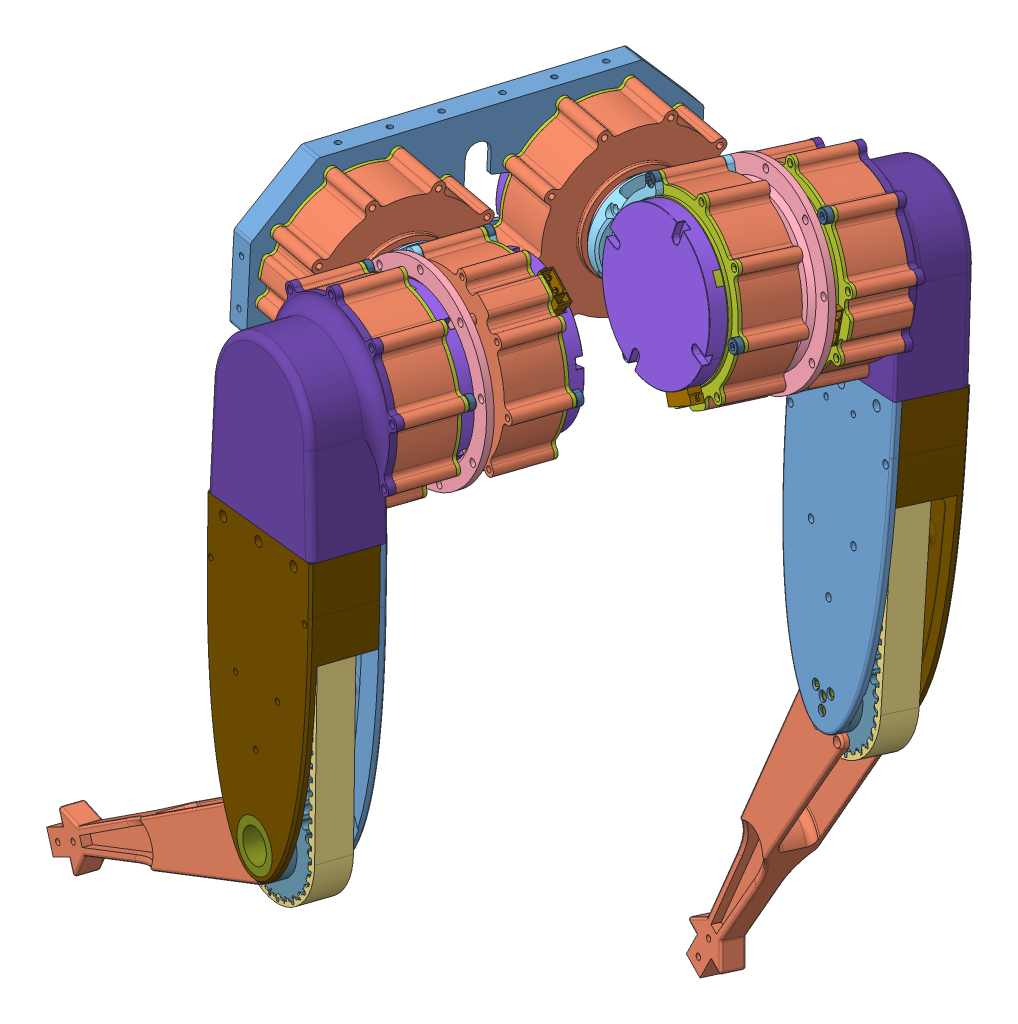
SolidWorks assembly 机器狗-后腿, configuration 默认. Lengths in mm.
Overall size (324.11 409.94 394.79).
151 component instances, 23 part files, 5 mates.
Components (placement in the parent):
- 肩膀-1: 肩膀 [默认] at (23.8945 164.324 448.6383) x (-0.213046 0.068534 0.974636) z (0.017935 -0.997094 0.074033) size (175 10 85)
- 右后机械腿装配体-1: 右后机械腿装配体 [默认] at (42.485 112.8434 831.0435) x (-0.961203 -0.272852 -0.040505) z (0.193141 -0.560888 -0.805047) size (251.73 287.49 164.5)
  - CyberGearmotor.stp-1: CyberGearmotor.stp [默认] at (-142.9395 145.7297 202.822) x (0.962425 -0.140801 0.232192) z (-0.142242 0.466971 0.872757) size (96.28 96.17 36.5)
    - ASM0002_ASM_1_ASM.stp-1: ASM0002_ASM_1_ASM.stp [默认] at origin size (96.28 96.17 36.5)
      - ASM0002_ASM_1_ASM_1_ASM.stp-1: ASM0002_ASM_1_ASM_1_ASM.stp [默认] at origin size (96.28 96.17 36.5)
        - 0714_ASM_1_ASM_1_ASM_1_ASM.stp-1: 0714_ASM_1_ASM_1_ASM_1_ASM.stp [默认] at origin size (96.28 96.17 36.5)
          - 3_1_02_067_0003_ASM_ASM_1_ASM_1_ASM.stp-1: 3_1_02_067_0003_ASM_ASM_1_ASM_1_ASM.stp [默认] at origin size (96.28 96.17 36.5)
            - 3_1_02_067_0003_ASM_1_ASM_1_ASM_ASM.stp-1: 3_1_02_067_0003_ASM_1_ASM_1_ASM_ASM.stp [默认] at origin size (96.28 96.17 36.5)
              - 1_1_06_EB673-504_1_1_1_1_1.stp-1: 1_1_06_EB673-504_1_1_1_1_1.stp [默认] at (39.8324 39.833 -22) size (79.19 78.95 25.5)
              - 1_2_04_670601_1_1_1_1_1.stp-1: 1_2_04_670601_1_1_1_1_1.stp [默认] at (93.9161 79.9966 -44) size (37 37 4)
              - 1_1_02_EB671-500_1_1_1_1_1.stp-1: 1_1_02_EB671-500_1_1_1_1_1.stp [默认] at (93.9161 79.9966 -44.4) x (-0.960973 0.276644 0) z (0 0 1) size (33 33 8.5)
              - 1_2_04_694000_1_1_1_1_1.stp-1: 1_2_04_694000_1_1_1_1_1.stp [默认] at (93.9161 79.9966 -44.5) size (11 11 4)
              - 1_2_06_000213_1_1_1_1_1.stp-1: 1_2_06_000213_1_1_1_1_1.stp [默认] at (93.9161 79.9966 -45.5) size (38.8 36.2 1.5)
              - 1_1_31_QT-642_1_1_1_1_1.stp-1: 1_1_31_QT-642_1_1_1_1_1.stp [默认] at (93.9161 79.9966 -22) x (-0.970555 -0.24088 0) z (0 0 -1) size (79.5 79.36 6)
              - 1_1_06_EB673-502_1_1_1_1_1.stp-1: 1_1_06_EB673-502_1_1_1_1_1.stp [默认] at (93.9161 79.9966 -13) x (-0.515958 -0.856614 0) z (0 0 -1) size (63 63 8)
            - 0518_ASM_2_ASM_1_ASM_1_ASM_1_AS_ASM.stp-1: 0518_ASM_2_ASM_1_ASM_1_ASM_1_AS_ASM.stp [默认] at (93.9161 79.9966 -17.235) x (0.235897 -0.971778 0) z (0 0 1) size (15.5 11.3 5.2)
              - 12345_ASM_1_ASM_2_ASM_1_ASM_1_A_ASM.stp-1: 12345_ASM_1_ASM_2_ASM_1_ASM_1_A_ASM.stp [默认] at origin size (15.5 11.3 5.2)
                - DUANZI_1_3_1_1_1_1_1_1.stp-1: DUANZI_1_3_1_1_1_1_1_1.stp [默认] at (-0.1798 16.5474 0.4329) x (0 0 -1) z (0 1 0) size (5.2 15.5 11.3)
        - LUODING_1_1.stp-1: LUODING_1_1.stp [默认] at (119.9375 52.9941 -20.5) x (-1 0 0) z (0 1 0) size (5.68 3 5.68)
        - LUODING_1_1.stp-2: LUODING_1_1.stp [默认] at (104.2902 116.0331 -20.5) x (-1 0 0) z (0 1 0) size (5.68 3 5.68)
        - LUODING_1_1.stp-3: LUODING_1_1.stp [默认] at (57.5205 70.9626 -20.5) x (-1 0 0) z (0 1 0) size (5.68 3 5.68)
    - 0411-2_4_1_3_1.stp-1: 0411-2_4_1_3_1.stp [默认] at (93.9161 79.9964 -17.5) x (0.235904 -0.971776 0) z (0 0 1) size (58 56.68 1.62)
  - 带轮-1: 带轮 [默认] at (-24.4468 170.8219 131.3671) x (-0.343989 -0.850087 0.398778) z (-0.142242 0.466971 0.872757) size (43.22 43.22 15)
  - 带轮挡边-1: 带轮挡边 [默认] at (-26.5804 177.8265 144.4584) x (-0.343989 -0.850087 0.398778) z (-0.142242 0.466971 0.872757) size (50 50 4)
  - 带轮挡边-2: 带轮挡边 [默认] at (-23.8778 168.9541 127.8761) x (-0.748404 0.526319 -0.403584) z (-0.142242 0.466971 0.872757) size (50 50 4)
  - 膝关节带轮-1: 膝关节带轮 [默认] at (-1.5747 18.1199 216.7985) x (-0.235503 -0.872369 0.428382) z (-0.142242 0.466971 0.872757) size (43.22 43.22 23)
  - 轴承-1: 轴承 [默认] at (0.6262 46.0224 223.4251) x (-0.92983 0.239281 -0.279572) z (0.142242 -0.466971 -0.872757) size (23 23 4)
  - 轴承-2: 轴承 [默认] at (3.2577 37.3834 207.2791) x (0.611134 0.73503 -0.293678) z (0.142242 -0.466971 -0.872757) size (23 23 4)
  - 膝关节转轴-1: 膝关节转轴 [默认] at (0.2706 47.1898 225.607) x (-0.926053 0.2486 -0.283942) z (0.142242 -0.466971 -0.872757) size (21 21 29)
  - 大腿根部SLDPRT-3: 大腿根部SLDPRT [默认] at (-70.696 232.4841 116.0443) x (0.0622 0.884197 -0.462955) z (0.142242 -0.466971 -0.872757) size (94.61 80.08 30.19)
  - 大腿前部-1: 大腿前部 [默认] at (-1.8386 102.8642 162.2464) x (0.97377 0.224213 0.038739) z (0.177593 -0.855375 0.486615) size (62 27.01 128.98)
  - 大腿前部盖子-1: 大腿前部盖子 [默认] at (-21.6364 113.2974 187.8113) x (-0.97377 -0.224213 -0.038739) z (0.177593 -0.855375 0.486615) size (62 3.5 129)
  - 小腿2-1: 小腿2 [默认] at (64.4519 33.7491 233.5195) x (0.961408 -0.144603 0.23406) z (0.235503 0.872369 -0.428382) size (141.69 21.45 28.63)
  - 5m同步带1-1: 5m同步带1 [默认] at (2.0151 41.7325 213.343) x (0.142242 -0.466971 -0.872757) z (0.177593 -0.855375 0.486615) size (15 46.9 201.91)
  - 连接盘-1: 连接盘 [默认] at (-33.7648 199.3725 183.8929) x (-0.075296 0.874063 -0.479942) z (-0.986964 -0.133983 -0.089167) size (80.5 13.5 80.5)
  - CyberGearmotor.stp-2: CyberGearmotor.stp [默认] at (75.7649 194.8202 259.7508) x (-0.509024 0.72169 -0.469103) z (-0.142242 0.466971 0.872757) size (96.28 96.17 36.5)
    - ASM0002_ASM_1_ASM.stp-1: ASM0002_ASM_1_ASM.stp [默认] at origin size (96.28 96.17 36.5)
      - ASM0002_ASM_1_ASM_1_ASM.stp-1: ASM0002_ASM_1_ASM_1_ASM.stp [默认] at origin size (96.28 96.17 36.5)
        - 0714_ASM_1_ASM_1_ASM_1_ASM.stp-1: 0714_ASM_1_ASM_1_ASM_1_ASM.stp [默认] at origin size (96.28 96.17 36.5)
          - 3_1_02_067_0003_ASM_ASM_1_ASM_1_ASM.stp-1: 3_1_02_067_0003_ASM_ASM_1_ASM_1_ASM.stp [默认] at origin size (96.28 96.17 36.5)
            - 3_1_02_067_0003_ASM_1_ASM_1_ASM_ASM.stp-1: 3_1_02_067_0003_ASM_1_ASM_1_ASM_ASM.stp [默认] at origin size (96.28 96.17 36.5)
              - 1_1_06_EB673-504_1_1_1_1_1.stp-1: 1_1_06_EB673-504_1_1_1_1_1.stp [默认] at (39.8324 39.833 -22) size (79.19 78.95 25.5)
              - 1_2_04_670601_1_1_1_1_1.stp-1: 1_2_04_670601_1_1_1_1_1.stp [默认] at (93.9161 79.9966 -44) size (37 37 4)
              - 1_1_02_EB671-500_1_1_1_1_1.stp-1: 1_1_02_EB671-500_1_1_1_1_1.stp [默认] at (93.9161 79.9966 -44.4) x (-0.960973 0.276644 0) z (0 0 1) size (33 33 8.5)
              - 1_2_04_694000_1_1_1_1_1.stp-1: 1_2_04_694000_1_1_1_1_1.stp [默认] at (93.9161 79.9966 -44.5) size (11 11 4)
              - 1_2_06_000213_1_1_1_1_1.stp-1: 1_2_06_000213_1_1_1_1_1.stp [默认] at (93.9161 79.9966 -45.5) size (38.8 36.2 1.5)
              - 1_1_31_QT-642_1_1_1_1_1.stp-1: 1_1_31_QT-642_1_1_1_1_1.stp [默认] at (93.9161 79.9966 -22) x (-0.970555 -0.24088 0) z (0 0 -1) size (79.5 79.36 6)
              - 1_1_06_EB673-502_1_1_1_1_1.stp-1: 1_1_06_EB673-502_1_1_1_1_1.stp [默认] at (93.9161 79.9966 -13) x (-0.515958 -0.856614 0) z (0 0 -1) size (63 63 8)
            - 0518_ASM_2_ASM_1_ASM_1_ASM_1_AS_ASM.stp-1: 0518_ASM_2_ASM_1_ASM_1_ASM_1_AS_ASM.stp [默认] at (93.9161 79.9966 -17.235) x (0.235897 -0.971778 0) z (0 0 1) size (15.5 11.3 5.2)
              - 12345_ASM_1_ASM_2_ASM_1_ASM_1_A_ASM.stp-1: 12345_ASM_1_ASM_2_ASM_1_ASM_1_A_ASM.stp [默认] at origin size (15.5 11.3 5.2)
                - DUANZI_1_3_1_1_1_1_1_1.stp-1: DUANZI_1_3_1_1_1_1_1_1.stp [默认] at (-0.1798 16.5474 0.4329) x (0 0 -1) z (0 1 0) size (5.2 15.5 11.3)
        - LUODING_1_1.stp-1: LUODING_1_1.stp [默认] at (119.9375 52.9941 -20.5) x (-1 0 0) z (0 1 0) size (5.68 3 5.68)
        - LUODING_1_1.stp-2: LUODING_1_1.stp [默认] at (104.2902 116.0331 -20.5) x (-1 0 0) z (0 1 0) size (5.68 3 5.68)
        - LUODING_1_1.stp-3: LUODING_1_1.stp [默认] at (57.5205 70.9626 -20.5) x (-1 0 0) z (0 1 0) size (5.68 3 5.68)
    - 0411-2_4_1_3_1.stp-1: 0411-2_4_1_3_1.stp [默认] at (93.9161 79.9964 -17.5) x (0.235904 -0.971776 0) z (0 0 1) size (58 56.68 1.62)
  - 肩关节连接器-1: 肩关节连接器 [默认] at (-36.3841 260.8063 150.3665) x (-0.509046 0.721677 -0.4691) z (0.848905 0.510999 -0.135057) size (67.92 36.71 40.7)
  - CyberGearmotor.stp-3: CyberGearmotor.stp [默认] at (56.3683 218.9179 320.1116) x (0.161386 -0.529819 -0.832614) z (0.956605 0.291387 0) size (96.28 96.17 36.5)
    - ASM0002_ASM_1_ASM.stp-1: ASM0002_ASM_1_ASM.stp [默认] at origin size (96.28 96.17 36.5)
      - ASM0002_ASM_1_ASM_1_ASM.stp-1: ASM0002_ASM_1_ASM_1_ASM.stp [默认] at origin size (96.28 96.17 36.5)
        - 0714_ASM_1_ASM_1_ASM_1_ASM.stp-1: 0714_ASM_1_ASM_1_ASM_1_ASM.stp [默认] at origin size (96.28 96.17 36.5)
          - 3_1_02_067_0003_ASM_ASM_1_ASM_1_ASM.stp-1: 3_1_02_067_0003_ASM_ASM_1_ASM_1_ASM.stp [默认] at origin size (96.28 96.17 36.5)
            - 3_1_02_067_0003_ASM_1_ASM_1_ASM_ASM.stp-1: 3_1_02_067_0003_ASM_1_ASM_1_ASM_ASM.stp [默认] at origin size (96.28 96.17 36.5)
              - 1_1_06_EB673-504_1_1_1_1_1.stp-1: 1_1_06_EB673-504_1_1_1_1_1.stp [默认] at (39.8324 39.833 -22) size (79.19 78.95 25.5)
              - 1_2_04_670601_1_1_1_1_1.stp-1: 1_2_04_670601_1_1_1_1_1.stp [默认] at (93.9161 79.9966 -44) size (37 37 4)
              - 1_1_02_EB671-500_1_1_1_1_1.stp-1: 1_1_02_EB671-500_1_1_1_1_1.stp [默认] at (93.9161 79.9966 -44.4) x (-0.960973 0.276644 0) z (0 0 1) size (33 33 8.5)
              - 1_2_04_694000_1_1_1_1_1.stp-1: 1_2_04_694000_1_1_1_1_1.stp [默认] at (93.9161 79.9966 -44.5) size (11 11 4)
              - 1_2_06_000213_1_1_1_1_1.stp-1: 1_2_06_000213_1_1_1_1_1.stp [默认] at (93.9161 79.9966 -45.5) size (38.8 36.2 1.5)
              - 1_1_31_QT-642_1_1_1_1_1.stp-1: 1_1_31_QT-642_1_1_1_1_1.stp [默认] at (93.9161 79.9966 -22) x (-0.970555 -0.24088 0) z (0 0 -1) size (79.5 79.36 6)
              - 1_1_06_EB673-502_1_1_1_1_1.stp-1: 1_1_06_EB673-502_1_1_1_1_1.stp [默认] at (93.9161 79.9966 -13) x (-0.515958 -0.856614 0) z (0 0 -1) size (63 63 8)
            - 0518_ASM_2_ASM_1_ASM_1_ASM_1_AS_ASM.stp-1: 0518_ASM_2_ASM_1_ASM_1_ASM_1_AS_ASM.stp [默认] at (93.9161 79.9966 -17.235) x (0.235897 -0.971778 0) z (0 0 1) size (15.5 11.3 5.2)
              - 12345_ASM_1_ASM_2_ASM_1_ASM_1_A_ASM.stp-1: 12345_ASM_1_ASM_2_ASM_1_ASM_1_A_ASM.stp [默认] at origin size (15.5 11.3 5.2)
                - DUANZI_1_3_1_1_1_1_1_1.stp-1: DUANZI_1_3_1_1_1_1_1_1.stp [默认] at (-0.1798 16.5474 0.4329) x (0 0 -1) z (0 1 0) size (5.2 15.5 11.3)
        - LUODING_1_1.stp-1: LUODING_1_1.stp [默认] at (119.9375 52.9941 -20.5) x (-1 0 0) z (0 1 0) size (5.68 3 5.68)
        - LUODING_1_1.stp-2: LUODING_1_1.stp [默认] at (104.2902 116.0331 -20.5) x (-1 0 0) z (0 1 0) size (5.68 3 5.68)
        - LUODING_1_1.stp-3: LUODING_1_1.stp [默认] at (57.5205 70.9626 -20.5) x (-1 0 0) z (0 1 0) size (5.68 3 5.68)
    - 0411-2_4_1_3_1.stp-1: 0411-2_4_1_3_1.stp [默认] at (93.9161 79.9964 -17.5) x (0.235904 -0.971776 0) z (0 0 1) size (58 56.68 1.62)
- 左后机械腿装配体-1: 左后机械腿装配体 [默认] at (137.0883 -41.1312 269.3926) x (0.991812 -0.063237 0.11095) z (-0.111258 -0.001369 0.993791) size (159.19 372.62 150.59)
  - CyberGearmotor.stp-1: CyberGearmotor.stp [默认] at (-142.9677 146.7561 185.5962) x (0.968253 -0.203796 0.14475) z (-0.114976 0.151089 0.981811) size (96.28 96.17 36.5)
    - ASM0002_ASM_1_ASM.stp-1: ASM0002_ASM_1_ASM.stp [默认] at origin size (96.28 96.17 36.5)
      - ASM0002_ASM_1_ASM_1_ASM.stp-1: ASM0002_ASM_1_ASM_1_ASM.stp [默认] at origin size (96.28 96.17 36.5)
        - 0714_ASM_1_ASM_1_ASM_1_ASM.stp-1: 0714_ASM_1_ASM_1_ASM_1_ASM.stp [默认] at origin size (96.28 96.17 36.5)
          - 3_1_02_067_0003_ASM_ASM_1_ASM_1_ASM.stp-1: 3_1_02_067_0003_ASM_ASM_1_ASM_1_ASM.stp [默认] at origin size (96.28 96.17 36.5)
            - 3_1_02_067_0003_ASM_1_ASM_1_ASM_ASM.stp-1: 3_1_02_067_0003_ASM_1_ASM_1_ASM_ASM.stp [默认] at origin size (96.28 96.17 36.5)
              - 1_1_06_EB673-504_1_1_1_1_1.stp-1: 1_1_06_EB673-504_1_1_1_1_1.stp [默认] at (39.8324 39.833 -22) size (79.19 78.95 25.5)
              - 1_2_04_670601_1_1_1_1_1.stp-1: 1_2_04_670601_1_1_1_1_1.stp [默认] at (93.9161 79.9966 -44) size (37 37 4)
              - 1_1_02_EB671-500_1_1_1_1_1.stp-1: 1_1_02_EB671-500_1_1_1_1_1.stp [默认] at (93.9161 79.9966 -44.4) x (-0.960973 0.276644 0) z (0 0 1) size (33 33 8.5)
              - 1_2_04_694000_1_1_1_1_1.stp-1: 1_2_04_694000_1_1_1_1_1.stp [默认] at (93.9161 79.9966 -44.5) size (11 11 4)
              - 1_2_06_000213_1_1_1_1_1.stp-1: 1_2_06_000213_1_1_1_1_1.stp [默认] at (93.9161 79.9966 -45.5) size (38.8 36.2 1.5)
              - 1_1_31_QT-642_1_1_1_1_1.stp-1: 1_1_31_QT-642_1_1_1_1_1.stp [默认] at (93.9161 79.9966 -22) x (-0.970555 -0.24088 0) z (0 0 -1) size (79.5 79.36 6)
              - 1_1_06_EB673-502_1_1_1_1_1.stp-1: 1_1_06_EB673-502_1_1_1_1_1.stp [默认] at (93.9161 79.9966 -13) x (-0.515958 -0.856614 0) z (0 0 -1) size (63 63 8)
            - 0518_ASM_2_ASM_1_ASM_1_ASM_1_AS_ASM.stp-1: 0518_ASM_2_ASM_1_ASM_1_ASM_1_AS_ASM.stp [默认] at (93.9161 79.9966 -17.235) x (0.235897 -0.971778 0) z (0 0 1) size (15.5 11.3 5.2)
              - 12345_ASM_1_ASM_2_ASM_1_ASM_1_A_ASM.stp-1: 12345_ASM_1_ASM_2_ASM_1_ASM_1_A_ASM.stp [默认] at origin size (15.5 11.3 5.2)
                - DUANZI_1_3_1_1_1_1_1_1.stp-1: DUANZI_1_3_1_1_1_1_1_1.stp [默认] at (-0.1798 16.5474 0.4329) x (0 0 -1) z (0 1 0) size (5.2 15.5 11.3)
        - LUODING_1_1.stp-1: LUODING_1_1.stp [默认] at (119.9375 52.9941 -20.5) x (-1 0 0) z (0 1 0) size (5.68 3 5.68)
        - LUODING_1_1.stp-2: LUODING_1_1.stp [默认] at (104.2902 116.0331 -20.5) x (-1 0 0) z (0 1 0) size (5.68 3 5.68)
        - LUODING_1_1.stp-3: LUODING_1_1.stp [默认] at (57.5205 70.9626 -20.5) x (-1 0 0) z (0 1 0) size (5.68 3 5.68)
    - 0411-2_4_1_3_1.stp-1: 0411-2_4_1_3_1.stp [默认] at (93.9161 79.9964 -17.5) x (0.235904 -0.971776 0) z (0 0 1) size (58 56.68 1.62)
  - 带轮-1: 带轮 [默认] at (-26.5163 194.7974 123.0899) x (-0.682793 -0.729895 0.032363) z (-0.114976 0.151089 0.981811) size (43.22 43.22 15)
  - 带轮挡边-1: 带轮挡边 [默认] at (-28.2409 197.0638 137.8171) x (-0.682793 -0.729895 0.032363) z (-0.114976 0.151089 0.981811) size (50 50 4)
  - 带轮挡边-2: 带轮挡边 [默认] at (-26.0564 194.1931 119.1627) x (-0.432175 0.882318 -0.186388) z (-0.114976 0.151089 0.981811) size (50 50 4)
  - 膝关节带轮-1: 膝关节带轮 [默认] at (-17.7229 50.8623 146.2695) x (-0.93026 0.33029 -0.159767) z (-0.114976 0.151089 0.981811) size (43.22 43.22 23)
  - 轴承-1: 轴承 [默认] at (0.7633 46.7268 167.9135) x (-0.724883 0.663028 -0.18692) z (0.114976 -0.151089 -0.981811) size (23 23 4)
  - 轴承-2: 轴承 [默认] at (2.8904 43.9316 149.75) x (0.870598 0.491289 0.026349) z (0.114976 -0.151089 -0.981811) size (23 23 4)
  - 膝关节转轴-1: 膝关节转轴 [默认] at (0.4759 47.1045 170.368) x (-0.717392 0.671027 -0.187274) z (0.114976 -0.151089 -0.981811) size (21 21 29)
  - 大腿根部SLDPRT-3: 大腿根部SLDPRT [默认] at (-72.9613 257.7727 130.3673) x (0.051984 0.987926 -0.145942) z (0.114976 -0.151089 -0.981811) size (94.61 80.08 30.19)
  - 大腿前部-1: 大腿前部 [默认] at (-3.2719 120.5903 129.0833) x (0.975319 0.204724 0.082711) z (0.188504 -0.967088 0.170898) size (62 27.01 128.98)
  - 大腿前部盖子-1: 大腿前部盖子 [默认] at (-22.2764 121.8579 157.2185) x (-0.975319 -0.204724 -0.082711) z (0.188504 -0.967088 0.170898) size (62 3.5 129)
  - 小腿2-1: 小腿2 [默认] at (-21.3684 -15.2067 168.7414) x (-0.348421 -0.931709 0.102576) z (0.93026 -0.33029 0.159767) size (141.69 21.45 28.63)
  - 5m同步带1-1: 5m同步带1 [默认] at (1.8414 46.0222 156.9444) x (0.114976 -0.151089 -0.981811) z (0.188504 -0.967088 0.170898) size (15 46.9 201.91)
  - 连接盘-1: 连接盘 [默认] at (-34.1913 204.3072 182.3485) x (-0.085987 0.983142 -0.161363) z (-0.98964 -0.102976 -0.100046) size (80.5 13.5 80.5)
  - CyberGearmotor.stp-2: CyberGearmotor.stp [默认] at (-146.2904 268.3897 208.758) x (0.350014 -0.918818 0.182384) z (-0.114976 0.151089 0.981811) size (96.28 96.17 36.5)
    - ASM0002_ASM_1_ASM.stp-1: ASM0002_ASM_1_ASM.stp [默认] at origin size (96.28 96.17 36.5)
      - ASM0002_ASM_1_ASM_1_ASM.stp-1: ASM0002_ASM_1_ASM_1_ASM.stp [默认] at origin size (96.28 96.17 36.5)
        - 0714_ASM_1_ASM_1_ASM_1_ASM.stp-1: 0714_ASM_1_ASM_1_ASM_1_ASM.stp [默认] at origin size (96.28 96.17 36.5)
          - 3_1_02_067_0003_ASM_ASM_1_ASM_1_ASM.stp-1: 3_1_02_067_0003_ASM_ASM_1_ASM_1_ASM.stp [默认] at origin size (96.28 96.17 36.5)
            - 3_1_02_067_0003_ASM_1_ASM_1_ASM_ASM.stp-1: 3_1_02_067_0003_ASM_1_ASM_1_ASM_ASM.stp [默认] at origin size (96.28 96.17 36.5)
              - 1_1_06_EB673-504_1_1_1_1_1.stp-1: 1_1_06_EB673-504_1_1_1_1_1.stp [默认] at (39.8324 39.833 -22) size (79.19 78.95 25.5)
              - 1_2_04_670601_1_1_1_1_1.stp-1: 1_2_04_670601_1_1_1_1_1.stp [默认] at (93.9161 79.9966 -44) size (37 37 4)
              - 1_1_02_EB671-500_1_1_1_1_1.stp-1: 1_1_02_EB671-500_1_1_1_1_1.stp [默认] at (93.9161 79.9966 -44.4) x (-0.960973 0.276644 0) z (0 0 1) size (33 33 8.5)
              - 1_2_04_694000_1_1_1_1_1.stp-1: 1_2_04_694000_1_1_1_1_1.stp [默认] at (93.9161 79.9966 -44.5) size (11 11 4)
              - 1_2_06_000213_1_1_1_1_1.stp-1: 1_2_06_000213_1_1_1_1_1.stp [默认] at (93.9161 79.9966 -45.5) size (38.8 36.2 1.5)
              - 1_1_31_QT-642_1_1_1_1_1.stp-1: 1_1_31_QT-642_1_1_1_1_1.stp [默认] at (93.9161 79.9966 -22) x (-0.970555 -0.24088 0) z (0 0 -1) size (79.5 79.36 6)
              - 1_1_06_EB673-502_1_1_1_1_1.stp-1: 1_1_06_EB673-502_1_1_1_1_1.stp [默认] at (93.9161 79.9966 -13) x (-0.515958 -0.856614 0) z (0 0 -1) size (63 63 8)
            - 0518_ASM_2_ASM_1_ASM_1_ASM_1_AS_ASM.stp-1: 0518_ASM_2_ASM_1_ASM_1_ASM_1_AS_ASM.stp [默认] at (93.9161 79.9966 -17.235) x (0.235897 -0.971778 0) z (0 0 1) size (15.5 11.3 5.2)
              - 12345_ASM_1_ASM_2_ASM_1_ASM_1_A_ASM.stp-1: 12345_ASM_1_ASM_2_ASM_1_ASM_1_A_ASM.stp [默认] at origin size (15.5 11.3 5.2)
                - DUANZI_1_3_1_1_1_1_1_1.stp-1: DUANZI_1_3_1_1_1_1_1_1.stp [默认] at (-0.1798 16.5474 0.4329) x (0 0 -1) z (0 1 0) size (5.2 15.5 11.3)
        - LUODING_1_1.stp-1: LUODING_1_1.stp [默认] at (119.9375 52.9941 -20.5) x (-1 0 0) z (0 1 0) size (5.68 3 5.68)
        - LUODING_1_1.stp-2: LUODING_1_1.stp [默认] at (104.2902 116.0331 -20.5) x (-1 0 0) z (0 1 0) size (5.68 3 5.68)
        - LUODING_1_1.stp-3: LUODING_1_1.stp [默认] at (57.5205 70.9626 -20.5) x (-1 0 0) z (0 1 0) size (5.68 3 5.68)
    - 0411-2_4_1_3_1.stp-1: 0411-2_4_1_3_1.stp [默认] at (93.9161 79.9964 -17.5) x (0.235904 -0.971776 0) z (0 0 1) size (58 56.68 1.62)
  - 肩关节连接器-1: 肩关节连接器 [默认] at (-42.6517 134.7106 191.8641) x (0.350039 -0.918808 0.182385) z (-0.929652 -0.364642 -0.052754) size (67.92 36.71 40.7)
  - CyberGearmotor.stp-3: CyberGearmotor.stp [默认] at (-142.1543 303.9583 248.4574) x (0.127941 -0.335558 -0.933291) z (-0.990208 -0.096202 -0.101155) size (96.28 96.17 36.5)
    - ASM0002_ASM_1_ASM.stp-1: ASM0002_ASM_1_ASM.stp [默认] at origin size (96.28 96.17 36.5)
      - ASM0002_ASM_1_ASM_1_ASM.stp-1: ASM0002_ASM_1_ASM_1_ASM.stp [默认] at origin size (96.28 96.17 36.5)
        - 0714_ASM_1_ASM_1_ASM_1_ASM.stp-1: 0714_ASM_1_ASM_1_ASM_1_ASM.stp [默认] at origin size (96.28 96.17 36.5)
          - 3_1_02_067_0003_ASM_ASM_1_ASM_1_ASM.stp-1: 3_1_02_067_0003_ASM_ASM_1_ASM_1_ASM.stp [默认] at origin size (96.28 96.17 36.5)
            - 3_1_02_067_0003_ASM_1_ASM_1_ASM_ASM.stp-1: 3_1_02_067_0003_ASM_1_ASM_1_ASM_ASM.stp [默认] at origin size (96.28 96.17 36.5)
              - 1_1_06_EB673-504_1_1_1_1_1.stp-1: 1_1_06_EB673-504_1_1_1_1_1.stp [默认] at (39.8324 39.833 -22) size (79.19 78.95 25.5)
              - 1_2_04_670601_1_1_1_1_1.stp-1: 1_2_04_670601_1_1_1_1_1.stp [默认] at (93.9161 79.9966 -44) size (37 37 4)
              - 1_1_02_EB671-500_1_1_1_1_1.stp-1: 1_1_02_EB671-500_1_1_1_1_1.stp [默认] at (93.9161 79.9966 -44.4) x (-0.960973 0.276644 0) z (0 0 1) size (33 33 8.5)
              - 1_2_04_694000_1_1_1_1_1.stp-1: 1_2_04_694000_1_1_1_1_1.stp [默认] at (93.9161 79.9966 -44.5) size (11 11 4)
              - 1_2_06_000213_1_1_1_1_1.stp-1: 1_2_06_000213_1_1_1_1_1.stp [默认] at (93.9161 79.9966 -45.5) size (38.8 36.2 1.5)
              - 1_1_31_QT-642_1_1_1_1_1.stp-1: 1_1_31_QT-642_1_1_1_1_1.stp [默认] at (93.9161 79.9966 -22) x (-0.970555 -0.24088 0) z (0 0 -1) size (79.5 79.36 6)
              - 1_1_06_EB673-502_1_1_1_1_1.stp-1: 1_1_06_EB673-502_1_1_1_1_1.stp [默认] at (93.9161 79.9966 -13) x (-0.515958 -0.856614 0) z (0 0 -1) size (63 63 8)
            - 0518_ASM_2_ASM_1_ASM_1_ASM_1_AS_ASM.stp-1: 0518_ASM_2_ASM_1_ASM_1_ASM_1_AS_ASM.stp [默认] at (93.9161 79.9966 -17.235) x (0.235897 -0.971778 0) z (0 0 1) size (15.5 11.3 5.2)
              - 12345_ASM_1_ASM_2_ASM_1_ASM_1_A_ASM.stp-1: 12345_ASM_1_ASM_2_ASM_1_ASM_1_A_ASM.stp [默认] at origin size (15.5 11.3 5.2)
                - DUANZI_1_3_1_1_1_1_1_1.stp-1: DUANZI_1_3_1_1_1_1_1_1.stp [默认] at (-0.1798 16.5474 0.4329) x (0 0 -1) z (0 1 0) size (5.2 15.5 11.3)
        - LUODING_1_1.stp-1: LUODING_1_1.stp [默认] at (119.9375 52.9941 -20.5) x (-1 0 0) z (0 1 0) size (5.68 3 5.68)
        - LUODING_1_1.stp-2: LUODING_1_1.stp [默认] at (104.2902 116.0331 -20.5) x (-1 0 0) z (0 1 0) size (5.68 3 5.68)
        - LUODING_1_1.stp-3: LUODING_1_1.stp [默认] at (57.5205 70.9626 -20.5) x (-1 0 0) z (0 1 0) size (5.68 3 5.68)
    - 0411-2_4_1_3_1.stp-1: 0411-2_4_1_3_1.stp [默认] at (93.9161 79.9964 -17.5) x (0.235904 -0.971776 0) z (0 0 1) size (58 56.68 1.62)
Mates (geometry in assembly coordinates):
- 重合1: coincident anti-aligned: plane of 肩膀-1 through (23.8945 164.324 448.6383) normal (0.976878 0.033253 0.211198); plane of 右后机械腿装配体-1/CyberGearmotor.stp-3/ASM0002_ASM_1_ASM.stp-1/ASM0002_ASM_1_ASM_1_ASM.stp-1/0714_ASM_1_ASM_1_ASM_1_ASM.stp-1/3_1_02_067_0003_ASM_ASM_1_ASM_1_ASM.stp-1/3_1_02_067_0003_ASM_1_ASM_1_ASM_ASM.stp-1/1_1_31_QT-642_1_1_1_1_1.stp-1 through (4.7204 170.492 536.3555) normal (-0.976878 -0.033253 -0.211198)
- 同心1: concentric anti-aligned: cylinder of 肩膀-1 through (2.7666 170.4255 535.9331) axis (0.976878 0.033253 0.211198) radius 32.5; cylinder of 右后机械腿装配体-1/CyberGearmotor.stp-3/ASM0002_ASM_1_ASM.stp-1/ASM0002_ASM_1_ASM_1_ASM.stp-1/0714_ASM_1_ASM_1_ASM_1_ASM.stp-1/3_1_02_067_0003_ASM_ASM_1_ASM_1_ASM.stp-1/3_1_02_067_0003_ASM_1_ASM_1_ASM_ASM.stp-1/1_1_06_EB673-502_1_1_1_1_1.stp-1 through (4.232 170.4754 536.2499) axis (-0.976878 -0.033253 -0.211198) radius 31.5
- 重合2: coincident anti-aligned: plane of 肩膀-1 through (23.8945 164.324 448.6383) normal (0.976878 0.033253 0.211198); plane of 左后机械腿装配体-1/CyberGearmotor.stp-3/ASM0002_ASM_1_ASM.stp-1/ASM0002_ASM_1_ASM_1_ASM.stp-1/0714_ASM_1_ASM_1_ASM_1_ASM.stp-1/3_1_02_067_0003_ASM_ASM_1_ASM_1_ASM.stp-1/3_1_02_067_0003_ASM_1_ASM_1_ASM_ASM.stp-1/1_1_31_QT-642_1_1_1_1_1.stp-1 through (23.8945 164.324 448.6383) normal (-0.976878 -0.033253 -0.211198)
- 同心2: concentric anti-aligned: cylinder of 肩膀-1 through (21.9408 164.2575 448.2159) axis (0.976878 0.033253 0.211198) radius 32.5; cylinder of 左后机械腿装配体-1/CyberGearmotor.stp-3/ASM0002_ASM_1_ASM.stp-1/ASM0002_ASM_1_ASM_1_ASM.stp-1/0714_ASM_1_ASM_1_ASM_1_ASM.stp-1/3_1_02_067_0003_ASM_ASM_1_ASM_1_ASM.stp-1/3_1_02_067_0003_ASM_1_ASM_1_ASM_ASM.stp-1/1_1_06_EB673-502_1_1_1_1_1.stp-1 through (23.4061 164.3074 448.5327) axis (-0.976878 -0.033253 -0.211198) radius 31.5
- 同心3: concentric aligned: cylinder of 肩膀-1 through (16.2262 198.2486 431.4171) axis (0.976878 0.033253 0.211198) radius 1.55; cylinder of 左后机械腿装配体-1/CyberGearmotor.stp-3/ASM0002_ASM_1_ASM.stp-1/ASM0002_ASM_1_ASM_1_ASM.stp-1/0714_ASM_1_ASM_1_ASM_1_ASM.stp-1/3_1_02_067_0003_ASM_ASM_1_ASM_1_ASM.stp-1/3_1_02_067_0003_ASM_1_ASM_1_ASM_ASM.stp-1/1_1_06_EB673-504_1_1_1_1_1.stp-1 through (27.0012 198.6153 433.7466) axis (0.976878 0.033253 0.211198) radius 1.25
